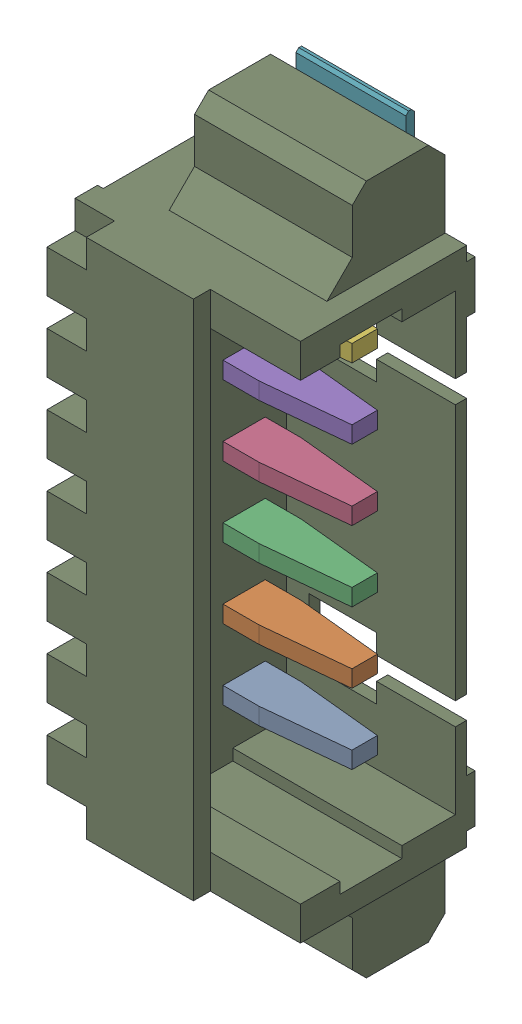
SolidWorks assembly J5, configuration Default. Lengths in mm.
Overall size (5.4 12.25 3.41).
10 component instances, 3 part files, 0 mates.
Components (placement in the parent):
- 653106131822-1: 653106131822 [Default] at (138.95 14.4999 1.69) x (0 1 0) z (0 0 1) size (12.25 5.4 3.41)
  - 6531xx131822_PIN-1: 6531xx131822_PIN [Default] at (-3.125 2.7 -0.425) x (1 0 0) z (0 -1 0) size (0.3 1.48 4.54)
  - 6531xx131822_PIN-2: 6531xx131822_PIN [Default] at (-1.875 2.7 -0.425) x (1 0 0) z (0 -1 0) size (0.3 1.48 4.54)
  - 6531xx131822_PIN-3: 6531xx131822_PIN [Default] at (-0.625 2.7 -0.425) x (1 0 0) z (0 -1 0) size (0.3 1.48 4.54)
  - 6531xx131822_PIN-4: 6531xx131822_PIN [Default] at (0.625 2.7 -0.425) x (1 0 0) z (0 -1 0) size (0.3 1.48 4.54)
  - 6531xx131822_PIN-5: 6531xx131822_PIN [Default] at (1.875 2.7 -0.425) x (1 0 0) z (0 -1 0) size (0.3 1.48 4.54)
  - 6531xx131822_PIN-6: 6531xx131822_PIN [Default] at (3.125 2.7 -0.425) x (1 0 0) z (0 -1 0) size (0.3 1.48 4.54)
  - 6531xx131822_PIN_FLANGE-1: 6531xx131822_PIN_FLANGE [Default] at (5 -0.045 -1.05) size (1.25 1.95 1.4)
  - 6531xx131822_PIN_FLANGE-2: 6531xx131822_PIN_FLANGE [Default] at (-5 -0.045 -1.05) x (-1 0 0) z (0 0 1) size (1.25 1.95 1.4)
  - 653106131822-1: 653106131822 [Default] at origin size (12.25 4.2 3.4)
